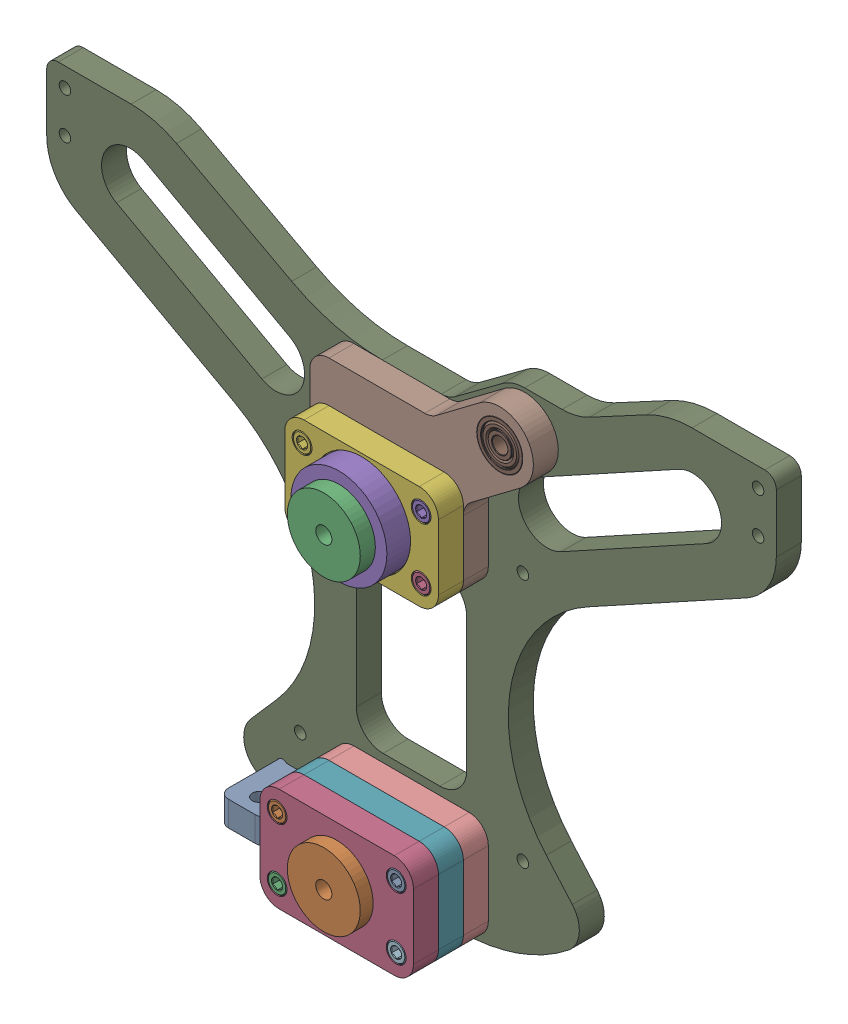
SolidWorks assembly MFG CW Fixed Base Asmbly, configuration Default. Lengths in mm.
Overall size (380 287.5 58.69).
32 component instances, 14 part files, 0 mates.
Components (placement in the parent):
- MFG CW Base Adj Block-1: MFG CW Base Adj Block [Default] at origin size (24 13 41.2)
- MFG CW Base Pivot Aft-1: MFG CW Base Pivot Aft [Default] at origin size (38 38 7.85)
- MFG CW Base Pivot Fwd-1: MFG CW Base Pivot Fwd [Default] at origin size (38 38 7.85)
- MFG CW Base Riser Block Aft 3-1: MFG CW Base Riser Block Aft 3 [Default] at origin size (80 54 13)
- MFG CW Base Riser Cylinder Fwd-1: MFG CW Base Riser Cylinder Fwd [Default] at origin size (50 50 13)
- MFG CW Base Riser Block Fwd 2-1: MFG CW Base Riser Block Fwd 2 [Default] at origin size (80 54 13)
- MFG CW Base Riser Block Aft 2-1: MFG CW Base Riser Block Aft 2 [Default] at origin size (80 54 13)
- MFG CW Base Rise Block Fwd 1-1: MFG CW Base Rise Block Fwd 1 [Default] at origin size (116.45 98 13)
- MFG CW Base Plate Sub Asmbly-1: MFG CW Base Plate Sub Asmbly [Default] at origin size (380 287.5 13)
  - MFG CW Base Plate-1: MFG CW Base Plate [Default] at origin size (380 287.5 13)
  - M6 x 1 Hex Nut-1: M6 x 1 Hex Nut [Default] at (-31 12.8 4.5) size (10 11.55 5)
  - M6 x 1 Hex Nut-2: M6 x 1 Hex Nut [Default] at (-31 45.2 4.5) size (10 11.55 5)
  - M6 x 1 Hex Nut-3: M6 x 1 Hex Nut [Default] at (31 12.8 4.5) size (10 11.55 5)
  - M6 x 1 Hex Nut-4: M6 x 1 Hex Nut [Default] at (31 45.2 4.5) size (10 11.55 5)
  - M6 x 1 Hex Nut-5: M6 x 1 Hex Nut [Default] at (-31 172.8 4.5) size (10 11.55 5)
  - M6 x 1 Hex Nut-6: M6 x 1 Hex Nut [Default] at (-31 205.2 4.5) size (10 11.55 5)
  - M6 x 1 Hex Nut-7: M6 x 1 Hex Nut [Default] at (31 172.8 4.5) size (10 11.55 5)
  - M6 x 1 Hex Nut-8: M6 x 1 Hex Nut [Default] at (31 205.2 4.5) size (10 11.55 5)
  - M6 x 1 Hex Nut-9: M6 x 1 Hex Nut [Default] at (-180.5 256 4.5) size (10 11.55 5)
  - M6 x 1 Hex Nut-10: M6 x 1 Hex Nut [Default] at (-180.5 277.5 4.5) size (10 11.55 5)
  - M6 x 1 Hex Nut-11: M6 x 1 Hex Nut [Default] at (180.5 256 4.5) size (10 11.55 5)
  - M6 x 1 Hex Nut-12: M6 x 1 Hex Nut [Default] at (180.5 277.5 4.5) size (10 11.55 5)
- MFG CW Base Riser Block Aft 1-1: MFG CW Base Riser Block Aft 1 [Default] at origin size (80 54 13)
- 628Z 8x24x8mm Ball Bearing-1: 628Z 8x24x8mm Ball Bearing [Default] at (58.9473 242.5 22) size (24 24 8)
- M6 x 1 mm 45 mm Length Socket Head Screw-1: M6 x 1 mm 45 mm Length Socket Head Screw [Default] at (31 12.8 46) size (10 10 51.29)
- M6 x 1 mm 45 mm Length Socket Head Screw-2: M6 x 1 mm 45 mm Length Socket Head Screw [Default] at (31 45.2 46) size (10 10 51.29)
- M6 x 1 mm 45 mm Length Socket Head Screw-3: M6 x 1 mm 45 mm Length Socket Head Screw [Default] at (-31 45.2 46) size (10 10 51.29)
- M6 x 1 mm 45 mm Length Socket Head Screw-4: M6 x 1 mm 45 mm Length Socket Head Screw [Default] at (-31 12.8 46) size (10 10 51.29)
- M6 x 1 mm 30 mm Length Socket Head Screw-1: M6 x 1 mm 30 mm Length Socket Head Screw [Default] at (31 172.8 33) size (10 10 36.29)
- M6 x 1 mm 30 mm Length Socket Head Screw-2: M6 x 1 mm 30 mm Length Socket Head Screw [Default] at (31 205.2 33) size (10 10 36.29)
- M6 x 1 mm 30 mm Length Socket Head Screw-3: M6 x 1 mm 30 mm Length Socket Head Screw [Default] at (-31 205.2 33) size (10 10 36.29)
- M6 x 1 mm 30 mm Length Socket Head Screw-4: M6 x 1 mm 30 mm Length Socket Head Screw [Default] at (-31 172.8 33) size (10 10 36.29)
